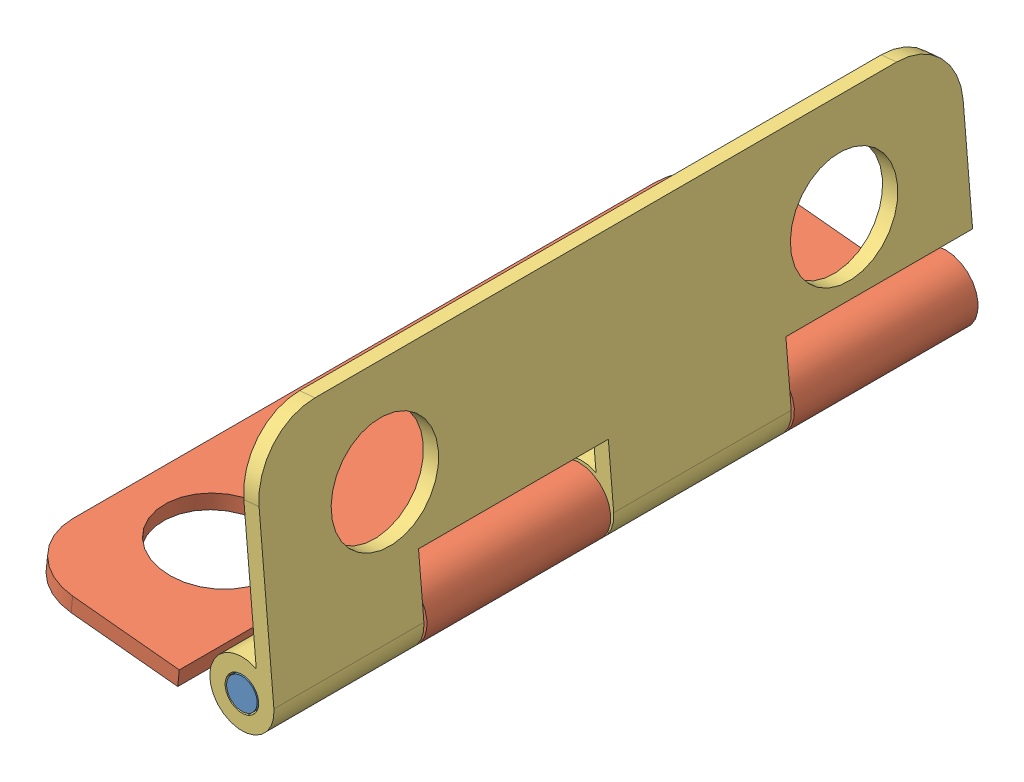
SolidWorks assembly DOBRADIÇA, configuration Valor predeterminado. Lengths in mm.
Overall size (8.72 8.71 23).
3 component instances, 3 part files, 10 mates.
Components (placement in the parent):
- EIXO DOB1-1: EIXO DOB1 [Valor predeterminado] at (22.878 0.0184 -13.9132) size (1 1 23)
- PEÇA DOB1-1: PEÇA DOB1 [Valor predeterminado] at (22.878 0.0184 -13.9132) x (0.099538 0.995034 0) z (0 0 1) size (2.1 8.55 23)
- PEÇA DOB2-1: PEÇA DOB2 [Valor predeterminado] at (22.878 0.0184 -13.9132) x (-0.996121 -0.087997 0) z (0 0 1) size (2.1 8.55 23)
Mates (geometry in assembly coordinates):
- Concêntrico1: concentric aligned: cylinder of EIXO DOB-1 through (-37.5431 9.057 11.5) axis (0 0 -1) radius 0.5; cylinder of PEÇA DOB-1 through (-37.5431 9.057 -5.5) axis (0 0 -1) radius 0.55
- Coincidente1: coincident aligned: plane of EIXO DOB-1 through (-37.5431 9.057 -11.5) normal (0 0 -1); plane of PEÇA DOB-1 through (-37.5431 9.057 -11.5) normal (0 0 -1)
- Coincidente2: coincident anti-aligned: plane of PEÇA DOB-1 through (-37.5431 9.057 6.5) normal (0 0 1); plane of PEÇA DOB-2 through (-37.5431 9.057 6.5) normal (0 0 -1)
- Concêntrico2: concentric anti-aligned: cylinder of EIXO DOB-1 through (-37.5431 9.057 11.5) axis (0 0 -1) radius 0.5; cylinder of PEÇA DOB-2 through (-37.5431 9.057 6.5) axis (0 0 1) radius 0.55
- Concêntrico3: concentric anti-aligned: cylinder of EIXO DOB1-1 through (22.878 0.0184 9.0868) axis (0 0 -1) radius 0.5; cylinder of PEÇA DOB2-1 through (22.878 0.0184 -4.7174) axis (0 0 1) radius 1.05
- Coincidente3: coincident aligned: plane of EIXO DOB1-1 through (22.878 0.0184 9.0868) normal (0 0 1); plane of PEÇA DOB2-1 through (22.878 0.0184 9.0868) normal (0 0 1)
- Concêntrico4: concentric aligned: cylinder of EIXO DOB1-1 through (22.878 0.0184 9.0868) axis (0 0 -1) radius 0.5; cylinder of PEÇA DOB1-1 through (22.878 0.0184 4.0868) axis (0 0 -1) radius 1.05
- Coincidente4: coincident aligned: plane of EIXO DOB1-1 through (22.878 0.0184 -13.9132) normal (0 0 -1); plane of PEÇA DOB1-1 through (22.878 0.0184 -13.9132) normal (0 0 -1)
- ÂnguloLimite3: limit planar angle = 3.141593 rad aligned: line of PEÇA DOB1-1 through (15.3605 0.2176 7.0868) axis (0 0 -1); line of PEÇA DOB2-1 through (22.7659 7.5377 -11.9132) axis (0 0 1)
- ÂnguloLimite9: limit planar angle = 1.382983 rad anti-aligned: plane of PEÇA DOB1-1 through (22.7735 -1.0264 -7.9132) normal (-0.099538 -0.995034 0); plane of PEÇA DOB2-1 through (23.9239 0.1108 -16.7174) normal (0.996121 0.087997 0)
